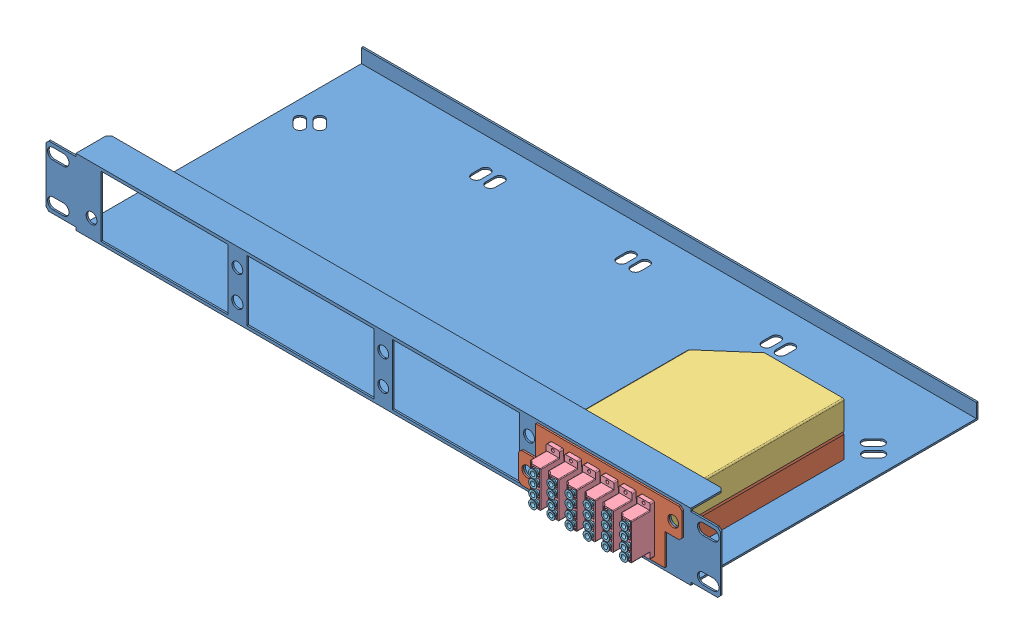
SolidWorks assembly MTP-Pannel, configuration Standard. Lengths in mm.
Overall size (482.6 47.8 225.51).
64 component instances, 5 part files, 6 mates.
Components (placement in the parent):
- 1U Rack Plate-1: 1U Rack Plate [Standard] at (-414.8398 -8.3387 0) size (482.6 47.8 205.5)
- MTP-Casette-1: MTP-Casette [Standard] at (-26.275 -1.825 1.2) size (117 43.2 150.01)
  - Cassette-1: Cassette [Standard] at (-81.5544 -7.2939 -1.2) size (117 43.2 131.2)
  - Cassette Lid-1: Cassette Lid [Standard] at (-38.8731 -6.65 -32.039) size (86.6 20.2 130)
  - LC-Adapter-1: LC-Adapter [Standard] at (-94.18 -5.525 16.25) x (0 1 0) z (0 0 1) size (34.9 10.05 34.47)
    - LC Adaptor-1: LC Adaptor [Standard] at (-28.4856 -9.35 -16.25) x (1 0 0) z (0 -1 0) size (34.9 25.75 9.35)
    - LC Adaptor Dust Cap-1: LC Adaptor Dust Cap [Standard] at (-27.05 -6.075 2.56) x (-0.837169 0.546944 0) z (-0.546944 -0.837169 0) size (5.75 16.66 5.75)
    - LC Adaptor Dust Cap-2: LC Adaptor Dust Cap [Standard] at (-20.85 -6.075 2.56) x (-0.837169 0.546944 0) z (-0.546944 -0.837169 0) size (5.75 16.66 5.75)
    - LC Adaptor Dust Cap-3: LC Adaptor Dust Cap [Standard] at (-14.05 -6.075 2.56) x (-0.837169 0.546944 0) z (-0.546944 -0.837169 0) size (5.75 16.66 5.75)
    - LC Adaptor Dust Cap-4: LC Adaptor Dust Cap [Standard] at (-7.85 -6.075 2.56) x (-0.837169 0.546944 0) z (-0.546944 -0.837169 0) size (5.75 16.66 5.75)
    - LC Adaptor Dust Cap-5: LC Adaptor Dust Cap [Standard] at (-27.05 -6.075 -31.91) x (0.972668 -0.232198 0) z (-0.232198 -0.972668 0) size (5.75 16.66 5.75)
    - LC Adaptor Dust Cap-6: LC Adaptor Dust Cap [Standard] at (-20.85 -6.075 -31.91) x (1 0 0) z (0 -1 0) size (5.75 16.66 5.75)
    - LC Adaptor Dust Cap-7: LC Adaptor Dust Cap [Standard] at (-14.05 -6.075 -31.91) x (0.97427 0.225385 0) z (0.225385 -0.97427 0) size (5.75 16.66 5.75)
    - LC Adaptor Dust Cap-8: LC Adaptor Dust Cap [Standard] at (-7.85 -6.075 -31.91) x (1 0 0) z (0 -1 0) size (5.75 16.66 5.75)
  - LC-Adapter-2: LC-Adapter [Standard] at (-81.18 -5.525 16.25) x (0 1 0) z (0 0 1) size (34.9 10.05 34.47)
    - LC Adaptor-1: LC Adaptor [Standard] at (-28.4856 -9.35 -16.25) x (1 0 0) z (0 -1 0) size (34.9 25.75 9.35)
    - LC Adaptor Dust Cap-1: LC Adaptor Dust Cap [Standard] at (-27.05 -6.075 2.56) x (-0.837169 0.546944 0) z (-0.546944 -0.837169 0) size (5.75 16.66 5.75)
    - LC Adaptor Dust Cap-2: LC Adaptor Dust Cap [Standard] at (-20.85 -6.075 2.56) x (-0.837169 0.546944 0) z (-0.546944 -0.837169 0) size (5.75 16.66 5.75)
    - LC Adaptor Dust Cap-3: LC Adaptor Dust Cap [Standard] at (-14.05 -6.075 2.56) x (-0.837169 0.546944 0) z (-0.546944 -0.837169 0) size (5.75 16.66 5.75)
    - LC Adaptor Dust Cap-4: LC Adaptor Dust Cap [Standard] at (-7.85 -6.075 2.56) x (-0.837169 0.546944 0) z (-0.546944 -0.837169 0) size (5.75 16.66 5.75)
    - LC Adaptor Dust Cap-5: LC Adaptor Dust Cap [Standard] at (-27.05 -6.075 -31.91) x (0.972668 -0.232198 0) z (-0.232198 -0.972668 0) size (5.75 16.66 5.75)
    - LC Adaptor Dust Cap-6: LC Adaptor Dust Cap [Standard] at (-20.85 -6.075 -31.91) x (1 0 0) z (0 -1 0) size (5.75 16.66 5.75)
    - LC Adaptor Dust Cap-7: LC Adaptor Dust Cap [Standard] at (-14.05 -6.075 -31.91) x (0.97427 0.225385 0) z (0.225385 -0.97427 0) size (5.75 16.66 5.75)
    - LC Adaptor Dust Cap-8: LC Adaptor Dust Cap [Standard] at (-7.85 -6.075 -31.91) x (1 0 0) z (0 -1 0) size (5.75 16.66 5.75)
  - LC-Adapter-3: LC-Adapter [Standard] at (-68.18 -5.525 16.25) x (0 1 0) z (0 0 1) size (34.9 10.05 34.47)
    - LC Adaptor-1: LC Adaptor [Standard] at (-28.4856 -9.35 -16.25) x (1 0 0) z (0 -1 0) size (34.9 25.75 9.35)
    - LC Adaptor Dust Cap-1: LC Adaptor Dust Cap [Standard] at (-27.05 -6.075 2.56) x (-0.837169 0.546944 0) z (-0.546944 -0.837169 0) size (5.75 16.66 5.75)
    - LC Adaptor Dust Cap-2: LC Adaptor Dust Cap [Standard] at (-20.85 -6.075 2.56) x (-0.837169 0.546944 0) z (-0.546944 -0.837169 0) size (5.75 16.66 5.75)
    - LC Adaptor Dust Cap-3: LC Adaptor Dust Cap [Standard] at (-14.05 -6.075 2.56) x (-0.837169 0.546944 0) z (-0.546944 -0.837169 0) size (5.75 16.66 5.75)
    - LC Adaptor Dust Cap-4: LC Adaptor Dust Cap [Standard] at (-7.85 -6.075 2.56) x (-0.837169 0.546944 0) z (-0.546944 -0.837169 0) size (5.75 16.66 5.75)
    - LC Adaptor Dust Cap-5: LC Adaptor Dust Cap [Standard] at (-27.05 -6.075 -31.91) x (0.972668 -0.232198 0) z (-0.232198 -0.972668 0) size (5.75 16.66 5.75)
    - LC Adaptor Dust Cap-6: LC Adaptor Dust Cap [Standard] at (-20.85 -6.075 -31.91) x (1 0 0) z (0 -1 0) size (5.75 16.66 5.75)
    - LC Adaptor Dust Cap-7: LC Adaptor Dust Cap [Standard] at (-14.05 -6.075 -31.91) x (0.97427 0.225385 0) z (0.225385 -0.97427 0) size (5.75 16.66 5.75)
    - LC Adaptor Dust Cap-8: LC Adaptor Dust Cap [Standard] at (-7.85 -6.075 -31.91) x (1 0 0) z (0 -1 0) size (5.75 16.66 5.75)
  - LC-Adapter-4: LC-Adapter [Standard] at (-55.18 -5.525 16.25) x (0 1 0) z (0 0 1) size (34.9 10.05 34.47)
    - LC Adaptor-1: LC Adaptor [Standard] at (-28.4856 -9.35 -16.25) x (1 0 0) z (0 -1 0) size (34.9 25.75 9.35)
    - LC Adaptor Dust Cap-1: LC Adaptor Dust Cap [Standard] at (-27.05 -6.075 2.56) x (-0.837169 0.546944 0) z (-0.546944 -0.837169 0) size (5.75 16.66 5.75)
    - LC Adaptor Dust Cap-2: LC Adaptor Dust Cap [Standard] at (-20.85 -6.075 2.56) x (-0.837169 0.546944 0) z (-0.546944 -0.837169 0) size (5.75 16.66 5.75)
    - LC Adaptor Dust Cap-3: LC Adaptor Dust Cap [Standard] at (-14.05 -6.075 2.56) x (-0.837169 0.546944 0) z (-0.546944 -0.837169 0) size (5.75 16.66 5.75)
    - LC Adaptor Dust Cap-4: LC Adaptor Dust Cap [Standard] at (-7.85 -6.075 2.56) x (-0.837169 0.546944 0) z (-0.546944 -0.837169 0) size (5.75 16.66 5.75)
    - LC Adaptor Dust Cap-5: LC Adaptor Dust Cap [Standard] at (-27.05 -6.075 -31.91) x (0.972668 -0.232198 0) z (-0.232198 -0.972668 0) size (5.75 16.66 5.75)
    - LC Adaptor Dust Cap-6: LC Adaptor Dust Cap [Standard] at (-20.85 -6.075 -31.91) x (1 0 0) z (0 -1 0) size (5.75 16.66 5.75)
    - LC Adaptor Dust Cap-7: LC Adaptor Dust Cap [Standard] at (-14.05 -6.075 -31.91) x (0.97427 0.225385 0) z (0.225385 -0.97427 0) size (5.75 16.66 5.75)
    - LC Adaptor Dust Cap-8: LC Adaptor Dust Cap [Standard] at (-7.85 -6.075 -31.91) x (1 0 0) z (0 -1 0) size (5.75 16.66 5.75)
  - LC-Adapter-5: LC-Adapter [Standard] at (-42.18 -5.525 16.25) x (0 1 0) z (0 0 1) size (34.9 10.05 34.47)
    - LC Adaptor-1: LC Adaptor [Standard] at (-28.4856 -9.35 -16.25) x (1 0 0) z (0 -1 0) size (34.9 25.75 9.35)
    - LC Adaptor Dust Cap-1: LC Adaptor Dust Cap [Standard] at (-27.05 -6.075 2.56) x (-0.837169 0.546944 0) z (-0.546944 -0.837169 0) size (5.75 16.66 5.75)
    - LC Adaptor Dust Cap-2: LC Adaptor Dust Cap [Standard] at (-20.85 -6.075 2.56) x (-0.837169 0.546944 0) z (-0.546944 -0.837169 0) size (5.75 16.66 5.75)
    - LC Adaptor Dust Cap-3: LC Adaptor Dust Cap [Standard] at (-14.05 -6.075 2.56) x (-0.837169 0.546944 0) z (-0.546944 -0.837169 0) size (5.75 16.66 5.75)
    - LC Adaptor Dust Cap-4: LC Adaptor Dust Cap [Standard] at (-7.85 -6.075 2.56) x (-0.837169 0.546944 0) z (-0.546944 -0.837169 0) size (5.75 16.66 5.75)
    - LC Adaptor Dust Cap-5: LC Adaptor Dust Cap [Standard] at (-27.05 -6.075 -31.91) x (0.972668 -0.232198 0) z (-0.232198 -0.972668 0) size (5.75 16.66 5.75)
    - LC Adaptor Dust Cap-6: LC Adaptor Dust Cap [Standard] at (-20.85 -6.075 -31.91) x (1 0 0) z (0 -1 0) size (5.75 16.66 5.75)
    - LC Adaptor Dust Cap-7: LC Adaptor Dust Cap [Standard] at (-14.05 -6.075 -31.91) x (0.97427 0.225385 0) z (0.225385 -0.97427 0) size (5.75 16.66 5.75)
    - LC Adaptor Dust Cap-8: LC Adaptor Dust Cap [Standard] at (-7.85 -6.075 -31.91) x (1 0 0) z (0 -1 0) size (5.75 16.66 5.75)
  - LC-Adapter-6: LC-Adapter [Standard] at (-29.18 -5.525 16.25) x (0 1 0) z (0 0 1) size (34.9 10.05 34.47)
    - LC Adaptor-1: LC Adaptor [Standard] at (-28.4856 -9.35 -16.25) x (1 0 0) z (0 -1 0) size (34.9 25.75 9.35)
    - LC Adaptor Dust Cap-1: LC Adaptor Dust Cap [Standard] at (-27.05 -6.075 2.56) x (-0.837169 0.546944 0) z (-0.546944 -0.837169 0) size (5.75 16.66 5.75)
    - LC Adaptor Dust Cap-2: LC Adaptor Dust Cap [Standard] at (-20.85 -6.075 2.56) x (-0.837169 0.546944 0) z (-0.546944 -0.837169 0) size (5.75 16.66 5.75)
    - LC Adaptor Dust Cap-3: LC Adaptor Dust Cap [Standard] at (-14.05 -6.075 2.56) x (-0.837169 0.546944 0) z (-0.546944 -0.837169 0) size (5.75 16.66 5.75)
    - LC Adaptor Dust Cap-4: LC Adaptor Dust Cap [Standard] at (-7.85 -6.075 2.56) x (-0.837169 0.546944 0) z (-0.546944 -0.837169 0) size (5.75 16.66 5.75)
    - LC Adaptor Dust Cap-5: LC Adaptor Dust Cap [Standard] at (-27.05 -6.075 -31.91) x (0.972668 -0.232198 0) z (-0.232198 -0.972668 0) size (5.75 16.66 5.75)
    - LC Adaptor Dust Cap-6: LC Adaptor Dust Cap [Standard] at (-20.85 -6.075 -31.91) x (1 0 0) z (0 -1 0) size (5.75 16.66 5.75)
    - LC Adaptor Dust Cap-7: LC Adaptor Dust Cap [Standard] at (-14.05 -6.075 -31.91) x (0.97427 0.225385 0) z (0.225385 -0.97427 0) size (5.75 16.66 5.75)
    - LC Adaptor Dust Cap-8: LC Adaptor Dust Cap [Standard] at (-7.85 -6.075 -31.91) x (1 0 0) z (0 -1 0) size (5.75 16.66 5.75)
Mates (geometry in assembly coordinates):
- Deckungsgleich1: coincident aligned: plane of 1U Rack Plate-1 through (-414.8398 -8.3387 0) normal (0 0 1); plane of assembly
- Deckungsgleich2: coincident aligned: plane of 1U Rack Plate-1 through (-21.2 0 -1.2) normal (0 1 0); plane of assembly
- Deckungsgleich3: coincident aligned: plane of 1U Rack Plate-1 through (0 -8.3387 0) normal (1 0 0); plane of assembly
- Deckungsgleich4: coincident: plane of 1U Rack Plate-1 through (-414.8398 -8.3387 0) normal (0 0 1); plane of MTP-Casette-1/Cassette-1 through (-107.8294 -9.1189 0) normal (0 0 -1)
- Konzentrisch1: concentric: cylinder of 1U Rack Plate-1 through (-32.6 -13.175 -1.4) axis (0 0 1) radius 3.9; cylinder of MTP-Casette-1/Cassette-1 through (-32.6 -13.175 -0.2) axis (0 0 1) radius 3.9
- Konzentrisch2: concentric aligned: cylinder of 1U Rack Plate-1 through (-136.95 -34.625 -1.4) axis (0 0 1) radius 3.9; cylinder of MTP-Casette-1/Cassette-1 through (-136.95 -34.625 -0.2) axis (0 0 1) radius 3.9
